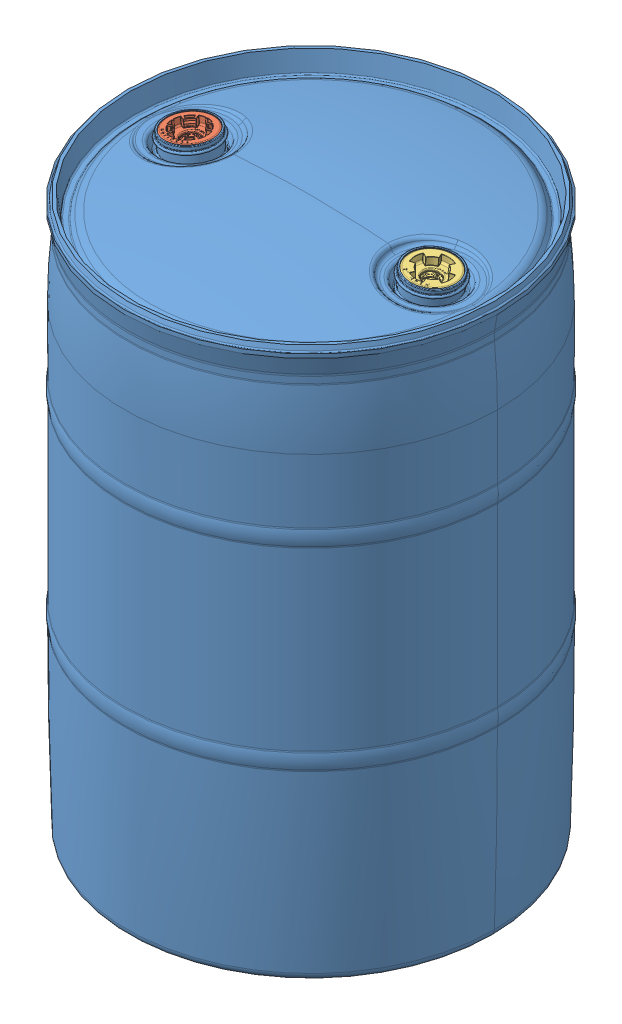
SolidWorks assembly 55 Gal Closed Top Plastic Drum, configuration Default. Lengths in mm.
Overall size (590.55 870.41 590.55).
3 component instances, 3 part files, 6 mates.
Components (placement in the parent):
- 55 Gal Closed Top Plastic Drum^55 Gal Closed Top Plastic Drum-1: 55 Gal Closed Top Plastic Drum^55 Gal Closed Top Plastic Drum [01] at origin size (590.55 869.95 590.55) (virtual)
- 2in_Buttress Drum Plug^55 Gal Closed Top Plastic Drum-2: 2in_Buttress Drum Plug^55 Gal Closed Top Plastic Drum [01] at (-190.0766 853.4048 0) x (0.995731 0.092306 0) z (0 0 1) size (73.03 27.19 73.03) (virtual)
- 2in_NPS Drum Plug^55 Gal Closed Top Plastic Drum-2: 2in_NPS Drum Plug^55 Gal Closed Top Plastic Drum [01] at (190.034 852.9443 0) x (0.995731 -0.092306 0) z (0 0 1) size (73.03 30.14 73.03) (virtual)
Mates (geometry in assembly coordinates):
- Coincident7: coincident: plane of 2in_Buttress Drum Plug^55 Gal Closed Top Plastic Drum-2 through (-190.0766 853.4048 0) normal (0 0 1); plane of assembly through (0 0 0) normal (0 0 1)
- Coincident8: coincident: plane of 55 Gal Closed Top Plastic Drum^55 Gal Closed Top Plastic Drum-1 through (-190.4003 856.8961 29.7656) normal (-0.092306 0.995731 0); plane of 2in_Buttress Drum Plug^55 Gal Closed Top Plastic Drum-2 through (-190.4003 856.8961 0) normal (0.092306 -0.995731 0)
- Concentric3: concentric: cylinder of 55 Gal Closed Top Plastic Drum^55 Gal Closed Top Plastic Drum-1 through (-186.4439 814.2173 0) axis (0.092306 -0.995731 0) radius 36.6395; cylinder of 2in_Buttress Drum Plug^55 Gal Closed Top Plastic Drum-2 through (-191.3222 866.8409 0) axis (0.092306 -0.995731 0) radius 36.5125
- Coincident9: coincident: plane of 55 Gal Closed Top Plastic Drum^55 Gal Closed Top Plastic Drum-1 through (190.5468 858.4768 25.4) normal (0.092306 0.995731 0); plane of 2in_NPS Drum Plug^55 Gal Closed Top Plastic Drum-2 through (190.5468 858.4768 0) normal (-0.092306 -0.995731 0)
- Concentric4: concentric: cylinder of 55 Gal Closed Top Plastic Drum^55 Gal Closed Top Plastic Drum-1 through (186.4439 814.2173 0) axis (-0.092306 -0.995731 0) radius 36.6395; cylinder of 2in_NPS Drum Plug^55 Gal Closed Top Plastic Drum-2 through (191.2795 866.3804 0) axis (-0.092306 -0.995731 0) radius 36.5125
- Coincident10: coincident: plane of 2in_NPS Drum Plug^55 Gal Closed Top Plastic Drum-2 through (190.034 852.9443 0) normal (0 0 1); plane of assembly through (0 0 0) normal (0 0 1)
